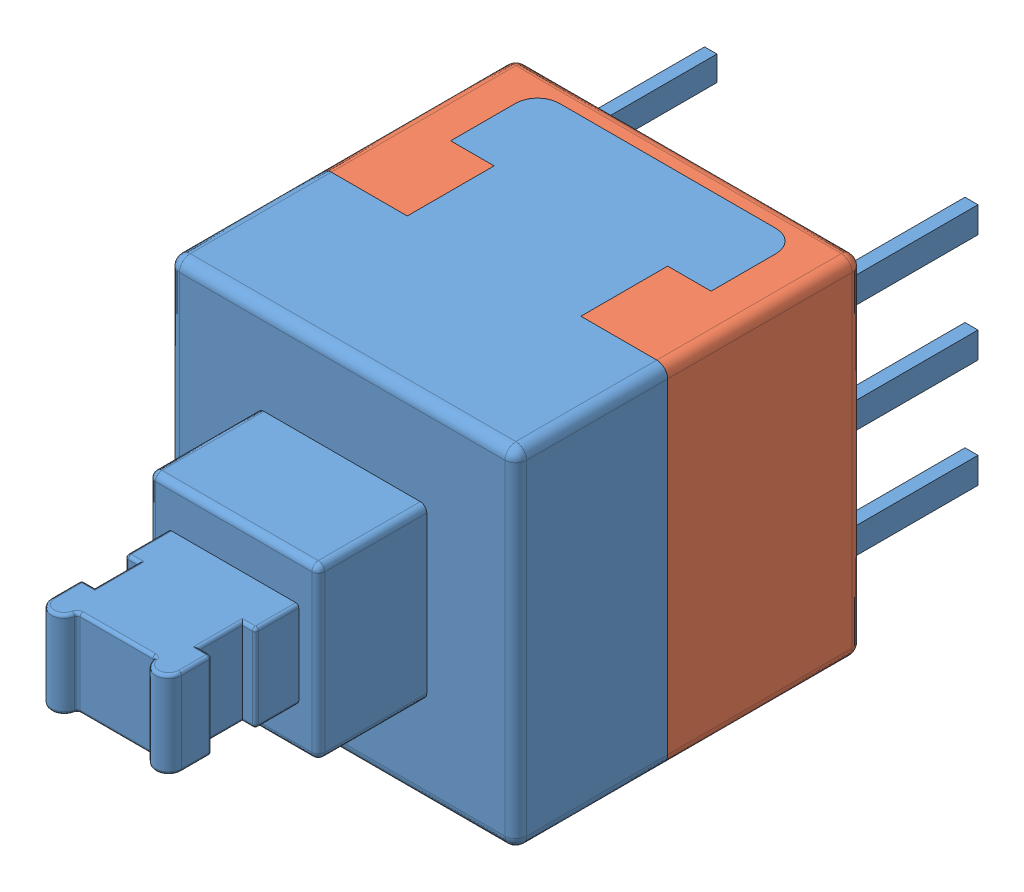
SolidWorks assembly switch, configuration 預設. Lengths in mm.
Overall size (8 8 17).
2 component instances, 2 part files, 3 mates.
Components (placement in the parent):
- switch_top-1: switch_top [預設] at (-3.878 0.8554 17) size (8 8 17)
- switch_bottom-1: switch_bottom [預設] at (-7.878 -3.1446 17) x (0 -1 0) z (-1 0 0) size (8 4.5 8)
Mates (geometry in assembly coordinates):
- 重合/共線/共點2: coincident: plane of assembly; plane of switch_top-1 through (-7.878 -3.1446 25) normal (0 -1 0); plane of switch_bottom-1 through (-1.378 -3.1446 18) normal (0 -1 0)
- 重合/共線/共點4: coincident: plane of assembly; plane of switch_top-1 through (0.122 -3.1446 25) normal (1 0 0); plane of switch_bottom-1 through (0.122 4.8554 17) normal (1 0 0)
- 重合/共線/共點5: coincident: plane of assembly; plane of switch_top-1 through (-1.378 4.8554 17.5) normal (0 0 -1); plane of switch_bottom-1 through (-1.378 4.8554 17.5) normal (0 0 1)
